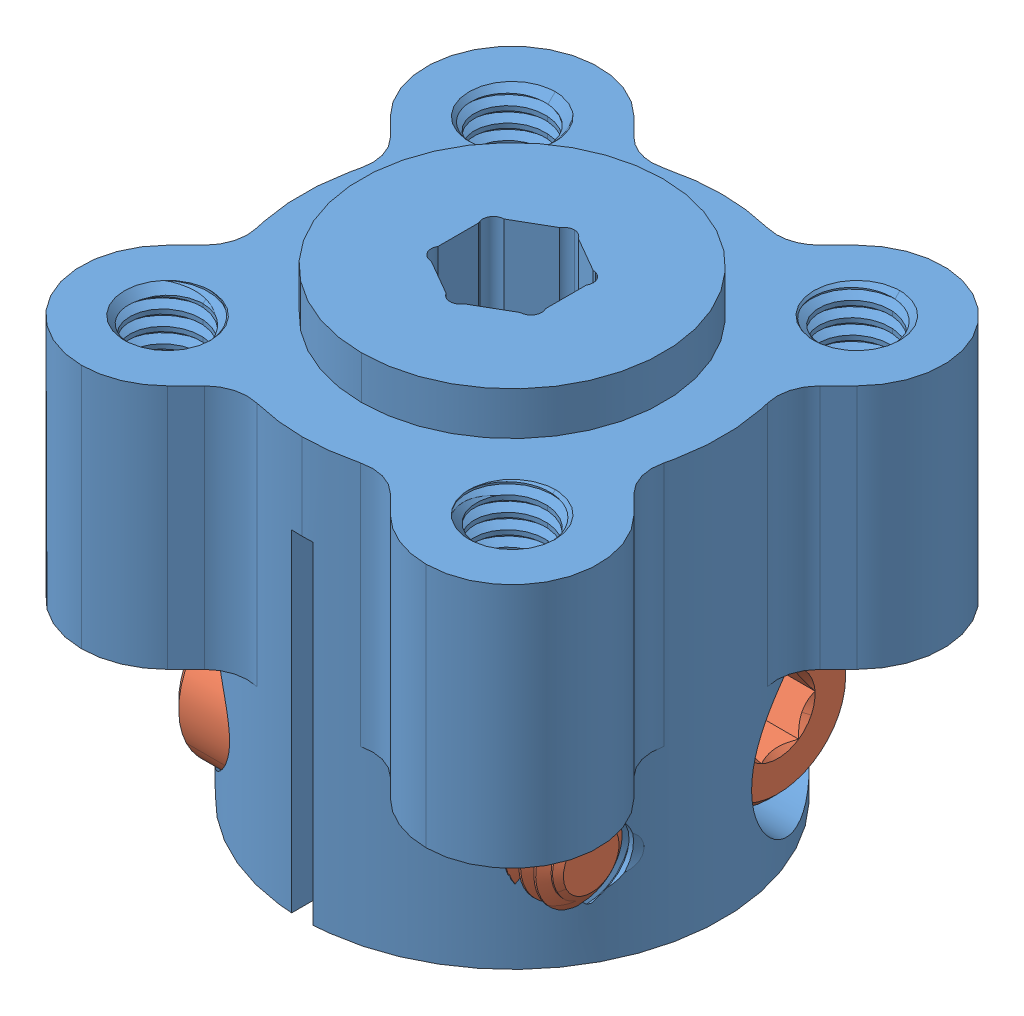
SolidWorks assembly 5mm Hyper Hex Hub 1310-0016-2005, configuration Default. Lengths in mm.
Overall size (24 21.68 24).
3 component instances, 2 part files, 0 mates.
Components (placement in the parent):
- 1310-0016-2005.STEP-1: 1310-0016-2005.STEP [Default] at (-10.1899 16.5861 -3.0378) size (24 21.4 24)
- 2800-0004-0012_90128A207.STEP-1: 2800-0004-0012_90128A207.STEP [Default] at (-18.9399 6.0861 -8.1178) x (0 0.437591 0.899174) z (-1 0 0) size (7 7 16.01)
- 2800-0004-0012_90128A207.STEP-2: 2800-0004-0012_90128A207.STEP [Default] at (-1.4399 6.0861 2.0422) x (0 0.437591 -0.899174) z (1 0 0) size (7 7 16.01)
